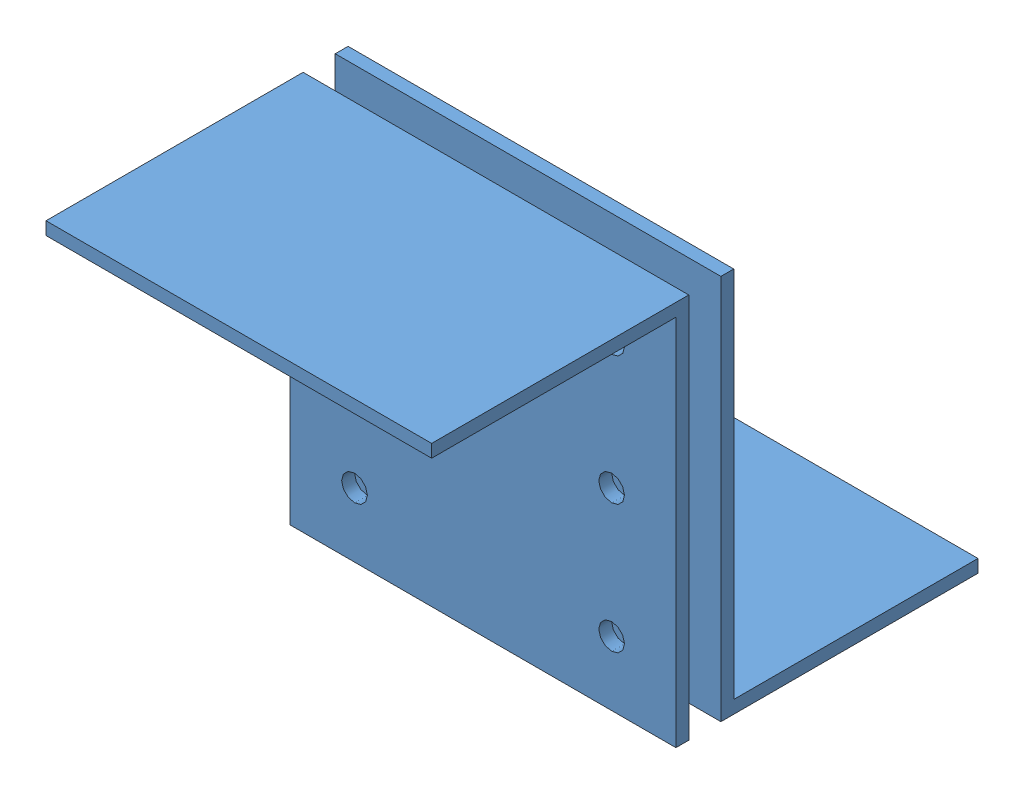
SolidWorks assembly Перемычка, configuration По умолчанию. Lengths in mm.
Overall size (60 60 85).
2 component instances, 1 part files, 4 mates.
Components (placement in the parent):
- Угольник-1: Угольник [По умолчанию] at origin size (60 60 40)
- Угольник-2: Угольник [По умолчанию] at (0 60 5) x (1 0 0) z (0 0 -1) size (60 60 40)
Mates (geometry in assembly coordinates):
- Совпадение1: coordinate: point of Угольник-1; point of assembly
- Расстояние1: distance = 5 mm anti-aligned: plane of Угольник-2 through (60 60 5) normal (0 0 -1); plane of Угольник-1 through (60 0 0) normal (0 0 1)
- Совпадение3: coincident aligned: plane of Угольник-1 through (0 0 0) normal (-1 0 0); plane of Угольник-2 through (0 60 5) normal (-1 0 0)
- Концентричный1: concentric anti-aligned: cylinder of Угольник-2 through (50 10 45) axis (0 0 -1) radius 2; cylinder of Угольник-1 through (50 10 -40) axis (0 0 1) radius 2
